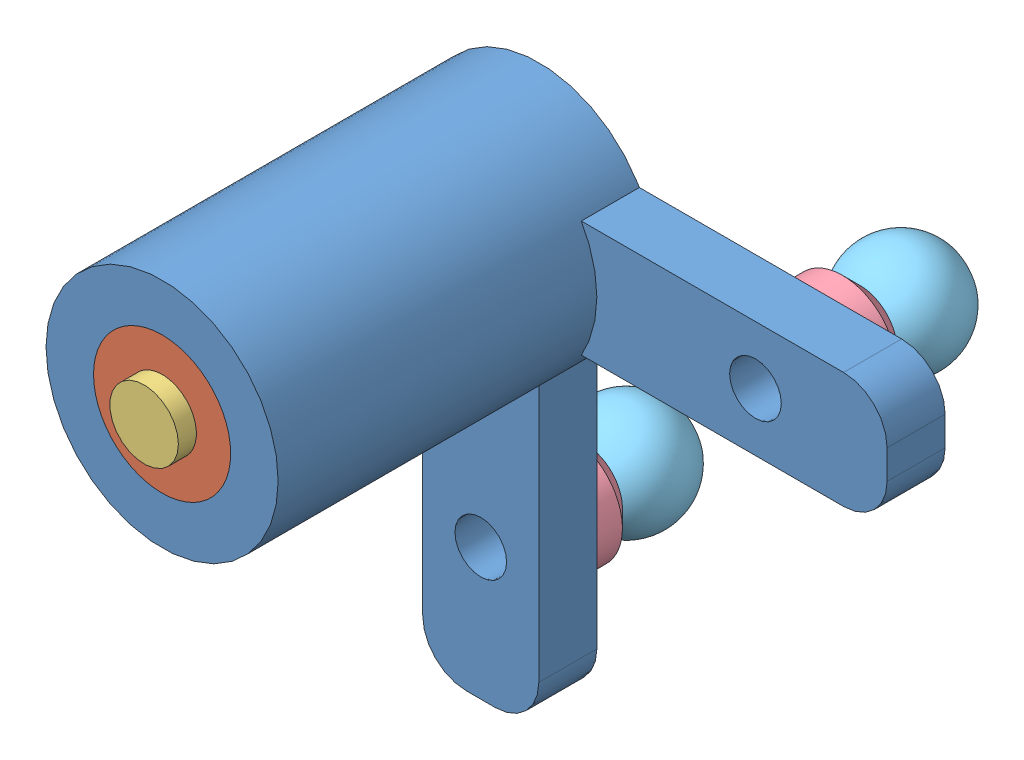
SolidWorks assembly Bell_Crank_Minor_Asm, configuration Default. Lengths in mm.
Overall size (22.86 22.86 22.89).
8 component instances, 5 part files, 14 mates.
Components (placement in the parent):
- Bell_Crank_Minor-1: Bell_Crank_Minor [Default] at (40.4366 -22.1226 -6.3081) size (22.86 22.86 16.48)
- 3.0mm_x_6.0mm_x_2.5mm_Ball_Bearing-1: 3.0mm_x_6.0mm_x_2.5mm_Ball_Bearing [Default] at (-7.455 3.178 -6.3081) size (6 6 2.5)
- 3.0mm_x_6.0mm_x_2.5mm_Ball_Bearing-2: 3.0mm_x_6.0mm_x_2.5mm_Ball_Bearing [Default] at (-7.455 3.178 7.6765) size (6 6 2.5)
- 3.0mm_Screw-1: 3.0mm_Screw [Default] at (-7.455 3.178 -8.0861) size (4 4 19.05)
- 2-56_Ball_Joint_Base-1: 2-56_Ball_Joint_Base [Default] at (4.5643 3.178 -6.3081) x (-0.923728 -0.383049 0) z (0 0 -1) size (4.78 4.78 2.03)
- 2-56_Ball_Joint_Base-2: 2-56_Ball_Joint_Base [Default] at (-7.455 -8.8412 -6.3081) x (-0.923728 -0.383049 0) z (0 0 -1) size (4.78 4.78 2.03)
- 2-56_Ball_Joint_Half_Sphere-1: 2-56_Ball_Joint_Half_Sphere [Default] at (-7.455 -8.8412 -10.1308) x (1 0 0) z (0 1 0) size (4.78 3.58 4.78)
- 2-56_Ball_Joint_Half_Sphere-2: 2-56_Ball_Joint_Half_Sphere [Default] at (4.5643 3.178 -10.1308) x (1 0 0) z (0 1 0) size (4.78 3.58 4.78)
Mates (geometry in assembly coordinates):
- Coincident1: coincident anti-aligned: axis of 3.0mm_x_6.0mm_x_2.5mm_Ball_Bearing-2 through (-7.455 3.178 10.1765) axis (0 0 -1); axis of Bell_Crank_Minor-1 through (-7.455 3.178 -3.7681) axis (0 0 1)
- Coincident2: coincident aligned: plane of Bell_Crank_Minor-1 through (-7.455 3.178 10.1765) normal (0 0 1); plane of 3.0mm_x_6.0mm_x_2.5mm_Ball_Bearing-2 through (-7.455 3.178 10.1765) normal (0 0 1)
- Coincident3: coincident anti-aligned: axis of Bell_Crank_Minor-1 through (-7.455 3.178 -3.7681) axis (0 0 1); axis of 3.0mm_x_6.0mm_x_2.5mm_Ball_Bearing-1 through (-7.455 3.178 -3.8081) axis (0 0 -1)
- Coincident4: coincident aligned: plane of Bell_Crank_Minor-1 through (10.325 5.718 -6.3081) normal (0 0 -1); plane of 3.0mm_x_6.0mm_x_2.5mm_Ball_Bearing-1 through (-7.455 3.178 -6.3081) normal (0 0 -1)
- Coincident5: coincident anti-aligned: axis of 3.0mm_x_6.0mm_x_2.5mm_Ball_Bearing-1 through (-7.455 3.178 -3.8081) axis (0 0 -1); axis of 3.0mm_Screw-1 through (-7.455 3.178 -6.3081) axis (0 0 1)
- Coincident6: coincident anti-aligned: plane of 3.0mm_x_6.0mm_x_2.5mm_Ball_Bearing-1 through (-7.455 3.178 -6.3081) normal (0 0 -1); plane of 3.0mm_Screw-1 through (-7.455 3.178 -6.3081) normal (0 0 1)
- Coincident7: coincident aligned: axis of 2-56_Ball_Joint_Base-1 through (4.5643 3.178 -7.5781) axis (0 0 1); axis of Bell_Crank_Minor-1 through (4.5643 3.178 -6.3081) axis (0 0 1)
- Coincident8: coincident anti-aligned: plane of Bell_Crank_Minor-1 through (10.325 5.718 -6.3081) normal (0 0 -1); plane of 2-56_Ball_Joint_Base-1 through (4.5643 3.178 -6.3081) normal (0 0 1)
- Coincident9: coincident anti-aligned: axis of 2-56_Ball_Joint_Base-1 through (4.5643 3.178 -8.3401) axis (0 0 1); axis of 2-56_Ball_Joint_Half_Sphere-2 through (4.5643 3.178 -8.602) axis (0 0 -1)
- Coincident10: coincident anti-aligned: plane of 2-56_Ball_Joint_Base-1 through (4.5643 3.178 -8.3401) normal (0 0 -1); plane of 2-56_Ball_Joint_Half_Sphere-2 through (4.5643 3.178 -8.3401) normal (0 0 1)
- Coincident11: coincident aligned: axis of 2-56_Ball_Joint_Base-2 through (-7.455 -8.8412 -7.5781) axis (0 0 1); axis of Bell_Crank_Minor-1 through (-7.455 -8.8412 -6.3081) axis (0 0 1)
- Coincident12: coincident anti-aligned: plane of Bell_Crank_Minor-1 through (10.325 5.718 -6.3081) normal (0 0 -1); plane of 2-56_Ball_Joint_Base-2 through (-7.455 -8.8412 -6.3081) normal (0 0 1)
- Coincident13: coincident anti-aligned: axis of 2-56_Ball_Joint_Base-2 through (-7.455 -8.8412 -8.3401) axis (0 0 1); axis of 2-56_Ball_Joint_Half_Sphere-1 through (-7.455 -8.8412 -8.602) axis (0 0 -1)
- Coincident14: coincident anti-aligned: plane of 2-56_Ball_Joint_Base-2 through (-7.455 -8.8412 -8.3401) normal (0 0 -1); plane of 2-56_Ball_Joint_Half_Sphere-1 through (-7.455 -8.8412 -8.3401) normal (0 0 1)
